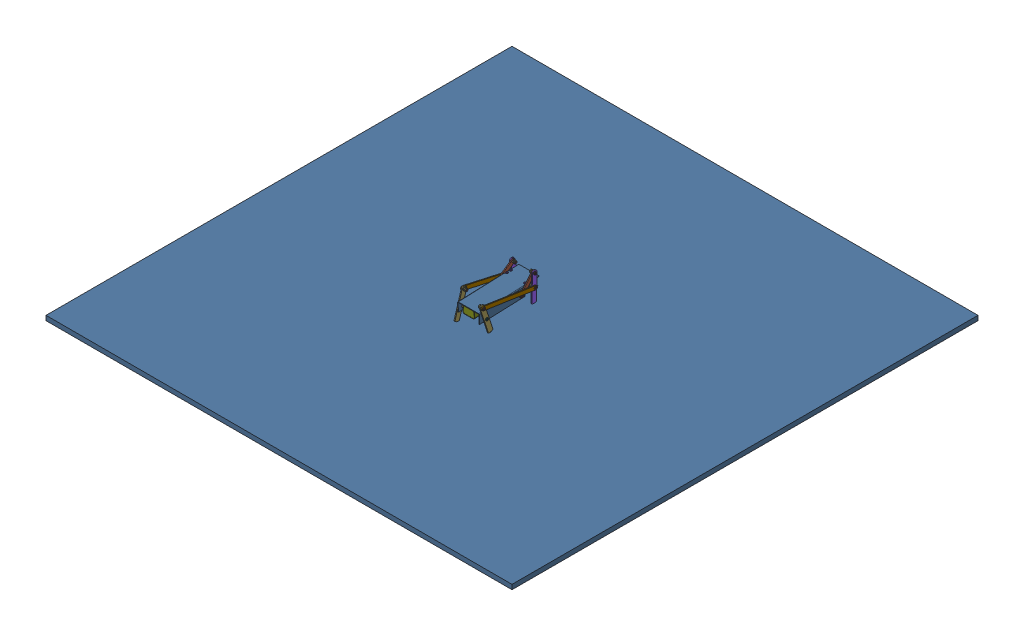
SolidWorks assembly Walking_Robot_(assembly), configuration Default. Lengths in mm.
Overall size (1000 78.05 1000).
80 component instances, 30 part files, 34 mates.
Components (placement in the parent):
- Walking_robot_(fixed_body)-1: Walking_robot_(fixed_body) [Default] at (18.9384 53.2482 -95.4555) x (0 -0.038992 0.99924) z (1 0 0) size (130 25.8 61.22)
  - ELENCO GEAR BOX 01-1: ELENCO GEAR BOX 01 [Default] at origin size (64.7 22.22 44.45)
  - ELENCO DC Motor 3V-1: ELENCO DC Motor 3V [Predeterminado] at (28.3843 11.811 0) x (0 0 1) z (-1 0 0) size (22.78 22.72 39.63)
    - ELENCO MOTOR HOUSING 01-1: ELENCO MOTOR HOUSING 01 [Predeterminado] at (0 0 24.0663) size (21.61 21.6 25.37)
    - ELENCO FRONT BUSHING-1: ELENCO FRONT BUSHING [Predeterminado] at (0 0 28.0103) x (0.939098 -0.34365 0) z (0 0 1) size (4.5 4.5 0.5)
    - ELENCO MOTOR BACK 01-1: ELENCO MOTOR BACK 01 [Predeterminado] at (0 0 4.731) x (-1 0 0) z (0 0 -1) size (21.23 21.59 3.58)
    - Terminal3V-1: Terminal3V [Predeterminado] at (0 -8.7 5.331) x (1 0 0) z (0 1 0) size (2.9 8 0.4)
    - Terminal3V-2: Terminal3V [Predeterminado] at (0 8.7 5.331) x (1 0 0) z (0 1 0) size (2.9 8 0.4)
    - ELENCO ARMATURE 01-1: ELENCO ARMATURE 01 [Predeterminado] at (0 0 36.9603) x (-0.892263 0.451515 0) z (0 0 1) size (17 16.86 36.46)
    - Enrolamento3V-1: Enrolamento3V [Predeterminado] at (2.0691 4.0889 14.4603) x (0.892263 -0.451515 0) z (0 0 1) size (7 3 16)
    - Enrolamento3V-2: Enrolamento3V [Predeterminado] at (-4.5756 -0.2525 14.4603) x (-0.055108 0.99848 0) z (0 0 1) size (7 3 16)
    - Enrolamento3V-3: Enrolamento3V [Predeterminado] at (2.5065 -3.8363 14.4603) x (-0.837155 -0.546965 0) z (0 0 1) size (7 3 16)
  - Walking_robot_(bolt_2_5x5)-1: Walking_robot_(bolt_2_5x5) [Default] at (-18.85 -1 19.55) x (0 -1 0) z (-0.551694 0 0.834047) size (6.57 4.4 4.4)
  - Walking_robot_(nut_2_5)-1: Walking_robot_(nut_2_5) [Default] at (-18.85 2.368 19.55) x (0.999996 0 -0.002907) z (0 -1 0) size (5.74 5.33 2.2)
  - Walking_robot_(bolt_2_5x5)-2: Walking_robot_(bolt_2_5x5) [Default] at (-18.85 -1 -19.55) x (0 -1 0) z (-0.551694 0 0.834047) size (6.57 4.4 4.4)
  - Walking_robot_(bolt_2_5x5)-3: Walking_robot_(bolt_2_5x5) [Default] at (-10.35 -1 19.55) x (0 -1 0) z (-0.551694 0 0.834047) size (6.57 4.4 4.4)
  - Walking_robot_(bolt_2_5x5)-4: Walking_robot_(bolt_2_5x5) [Default] at (-10.35 -1 -19.55) x (0 -1 0) z (-0.551694 0 0.834047) size (6.57 4.4 4.4)
  - Walking_robot_(nut_2_5)-2: Walking_robot_(nut_2_5) [Default] at (-18.85 2.368 -19.55) x (0.999996 0 -0.002907) z (0 -1 0) size (5.74 5.33 2.2)
  - Walking_robot_(nut_2_5)-3: Walking_robot_(nut_2_5) [Default] at (-10.35 2.368 19.55) x (0.999996 0 -0.002907) z (0 -1 0) size (5.74 5.33 2.2)
  - Walking_robot_(nut_2_5)-4: Walking_robot_(nut_2_5) [Default] at (-10.35 2.368 -19.55) x (0.999996 0 -0.002907) z (0 -1 0) size (5.74 5.33 2.2)
  - Walking_robot_(main_body)-1: Walking_robot_(main_body) [Default] at (42.9 -1 0) x (0 0 1) z (-1 0 0) size (46.5 20 130)
  - Walking_robot_(bolt_3x10)-1: Walking_robot_(bolt_3x10) [Default] at (3.9 11.5 -26.63) x (0 0 -1) z (1 0 0) size (11.98 5.4 5.4)
  - Walking_robot_(nut_3)-1: Walking_robot_(nut_3) [Default] at (3.9 11.5 -19.75) size (6.75 5.87 2.78)
  - Walking_robot_(bolt_3x10)-2: Walking_robot_(bolt_3x10) [Default] at (3.9 11.5 26.63) x (0 0 1) z (-0.923728 -0.383049 0) size (11.98 5.4 5.4)
  - Walking_robot_(nut_3)-7: Walking_robot_(nut_3) [Default] at (3.9 11.5 -22.25) size (6.75 5.87 2.78)
  - Walking_robot_(nut_3)-9: Walking_robot_(nut_3) [Default] at (3.9 11.5 19.75) size (6.75 5.87 2.78)
  - Walking_robot_(nut_3)-11: Walking_robot_(nut_3) [Default] at (3.9 11.5 17.25) size (6.75 5.87 2.78)
  - Walking_robot_(spacer1)-1: Walking_robot_(spacer1) [Default] at (3.9 11.5 23.25) size (6 6 1.38)
  - Walking_robot_(spacer1)-2: Walking_robot_(spacer1) [Default] at (3.9 11.5 -24.63) size (6 6 1.38)
  - Walking_robot_(spacer2)-1: Walking_robot_(spacer2) [Default] at (81.9 11.5 23.25) size (6 6 3.38)
  - Walking_robot_(spacer2)-2: Walking_robot_(spacer2) [Default] at (81.9 11.5 -26.63) size (6 6 3.38)
  - Walking_robot_(bolt_3x12)-2: Walking_robot_(bolt_3x12) [Default] at (81.9 11.5 28.634) x (0 0 1) z (-1 0 0) size (13.98 5.4 5.4)
  - Walking_robot_(bolt_3x12)-3: Walking_robot_(bolt_3x12) [Default] at (81.9 11.5 -28.634) x (0 0 -1) z (0.923728 0.383049 0) size (13.98 5.4 5.4)
  - Walking_robot_(nut_3)-8: Walking_robot_(nut_3) [Default] at (81.9 11.5 -22.25) size (6.75 5.87 2.78)
  - Walking_robot_(nut_3)-6: Walking_robot_(nut_3) [Default] at (81.9 11.5 -19.75) size (6.75 5.87 2.78)
  - Walking_robot_(nut_3)-12: Walking_robot_(nut_3) [Default] at (81.9 11.5 17.25) size (6.75 5.87 2.78)
  - Walking_robot_(nut_3)-10: Walking_robot_(nut_3) [Default] at (81.9 11.5 19.75) size (6.75 5.87 2.78)
  - PR2007 9 Volt Battery-1: PR2007 9 Volt Battery [Default] at (69.0962 8.1788 -0.6579) x (0 0 -1) z (0 1 0) size (25.25 47.81 16.41)
- ELENCO PINION  8T 01-1: ELENCO PINION  8T 01 [Default] at (18.9384 41.7805 -104.4855) x (0 -0.038992 0.99924) z (0.15938 0.986466 0.038494) size (4 4.57 4.57)
- Walking_robot_(assembled_first_axle)-1: Walking_robot_(assembled_first_axle) [Default] at (18.9384 31.4407 -126.8367) x (0 0.04551 -0.998964) z (1 0 0) size (20.72 20.72 40.75)
  - SHAFT 2 X 40-1: SHAFT 2 X 40 [Default] at (-15.216 11.557 0) x (-0.026375 -0.999652 0) z (0 0 1) size (2 2 40)
  - pCROWN GEAR 36T X 10T R01-1: pCROWN GEAR 36T X 10T R01 [Default] at (-15.216 11.557 -3.465) x (0 0 1) z (-0.986294 -0.164995 0) size (8.17 18 18)
  - ELENCO COLLAR 01-1: ELENCO COLLAR 01 [Default] at (-15.216 11.557 -15.875) x (0 0 -1) z (1 0 0) size (4.5 5 5)
  - ELENCO COLLAR 01-2: ELENCO COLLAR 01 [Default] at (-15.216 11.557 15.875) x (0 0 1) z (-0.923728 -0.383049 0) size (4.5 5 5)
- pCOMPOUND GEAR 40T X 10T GREEN R01-1: pCOMPOUND GEAR 40T X 10T GREEN R01 [Default] at (9.0224 42.2932 -111.1105) x (1 0 0) z (0 -0.686905 0.726747) size (6.08 20.96 20.96)
- Walking_robot_(assembled_second_axle)-1: Walking_robot_(assembled_second_axle) [Default] at (19.0544 21.5771 -145.3171) x (0 -0.376255 -0.926516) z (1 0 0) size (22.69 20.96 65.22)
  - SHAFT 3 X 52-1: SHAFT 3 X 52 [Default] at (-27.916 11.557 0) x (-0.087364 -0.996176 0) z (0 0 1) size (3 3 52)
  - ELENCO CRANK ARM 01-1: ELENCO CRANK ARM 01 [Default] at (-27.916 11.557 -23.446) x (0 0 -1) z (-0.996176 0.087364 0) size (10.76 6 14)
  - ELENCO CRANK ARM 01-2: ELENCO CRANK ARM 01 [Default] at (-27.916 11.557 23.2184) x (0 0 1) z (0.996176 -0.087364 0) size (10.76 6 14)
  - pCOMPOUND GEAR 40T X 10T GREEN R01a-1: pCOMPOUND GEAR 40T X 10T GREEN R01a [Default] at (-27.916 11.557 -12.742) x (0 0 -1) z (1 0 0) size (3.25 20.96 20.96)
  - Walking_robot_(nut_3)-1: Walking_robot_(nut_3) [Default] at (-35.8854 12.2559 20.7184) size (6.75 5.87 2.78)
  - Walking_robot_(nut_3)-2: Walking_robot_(nut_3) [Default] at (-19.9466 10.8581 -23.446) size (6.75 5.87 2.78)
  - Walking_robot_(bolt_3x10)-1: Walking_robot_(bolt_3x10) [Default] at (-35.8854 12.2559 30.5184) x (0 0 1) z (-1 0 0) size (11.98 5.4 5.4)
  - Walking_robot_(bolt_3x10)-2: Walking_robot_(bolt_3x10) [Default] at (-19.9466 10.8581 -30.746) x (0 0 -1) z (1 0 0) size (11.98 5.4 5.4)
- pCOMPOUND GEAR 40T X 10T RED R01-1: pCOMPOUND GEAR 40T X 10T RED R01 [Default] at (12.3884 42.7884 -123.8009) x (1 0 0) z (0 -0.583796 0.8119) size (6.08 20.96 20.96)
- Walking_robot_(legs)-1: Walking_robot_(legs) [Default] at (47.5729 47.9338 -116.7279) x (0 0.03187 0.999492) z (-1 0 0) size (10 60.41 2)
- Walking_robot_(legs)-2: Walking_robot_(legs) [Default] at (-7.6916 40.601 -130.5719) x (0 -0.233207 0.972427) z (-1 0 0) size (10 60.41 2)
- Walking_robot_(legs_lever1)-1: Walking_robot_(legs_lever1) [Default] at (-11.6916 60.0865 -36.7219) x (0 -0.976163 0.217038) z (1 0 0) size (8 120 2)
- Walking_robot_(legs_lever1)-2: Walking_robot_(legs_lever1) [Default] at (47.5729 60.9356 -21.2758) x (0 -0.988645 0.15027) z (1 0 0) size (8 120 2)
- Walking_robot_(floor)-1: Walking_robot_(floor) [Default] at (39.0613 0 -76.9839) x (1 0 0) z (0 1 0) size (1000 1000 10)
- Walking_robot_(assembled_legs_lever2)-1: Walking_robot_(assembled_legs_lever2) [Default] at (28.0217 115.6355 -43.4429) x (0 0.821287 0.570516) z (-1 0 0) size (8 48 11.98)
  - Walking_robot_(legs_lever2)-1: Walking_robot_(legs_lever2) [Default] at (-88.5069 13.1493 33.7132) size (8 48 2)
  - Walking_robot_(bolt_3x10)-1: Walking_robot_(bolt_3x10) [Default] at (-88.5069 37.6493 37.7132) x (0 0 1) z (-1 0 0) size (11.98 5.4 5.4)
  - Walking_robot_(nut_3)-1: Walking_robot_(nut_3) [Default] at (-88.5069 37.6493 31.2132) size (6.75 5.87 2.78)
  - Walking_robot_(nut_3)-2: Walking_robot_(nut_3) [Default] at (-88.5069 37.6493 28.7132) size (6.75 5.87 2.78)
- Walking_robot_(assembled_legs_lever2)-2: Walking_robot_(assembled_legs_lever2) [Default] at (9.8596 -13.0114 -161.6923) x (0 -0.637546 -0.770412) z (1 0 0) size (8 48 11.98)
  - Walking_robot_(legs_lever2)-1: Walking_robot_(legs_lever2) [Default] at (-88.5069 13.1493 33.7132) size (8 48 2)
  - Walking_robot_(bolt_3x10)-1: Walking_robot_(bolt_3x10) [Default] at (-88.5069 37.6493 37.7132) x (0 0 1) z (-1 0 0) size (11.98 5.4 5.4)
  - Walking_robot_(nut_3)-1: Walking_robot_(nut_3) [Default] at (-88.5069 37.6493 31.2132) size (6.75 5.87 2.78)
  - Walking_robot_(nut_3)-2: Walking_robot_(nut_3) [Default] at (-88.5069 37.6493 28.7132) size (6.75 5.87 2.78)
- Walking_robot_(assembled_front_legs)-1: Walking_robot_(assembled_front_legs) [Default] at (11.8596 55.1181 -101.788) x (0 0.31209 -0.950053) z (1 0 0) size (10 60.4 11.98)
  - Walking_robot_(bolt_3x10)-1: Walking_robot_(bolt_3x10) [Default] at (-88.5069 37.6493 37.7132) x (0 0 1) z (-1 0 0) size (11.98 5.4 5.4)
  - Walking_robot_(nut_3)-1: Walking_robot_(nut_3) [Default] at (-88.5069 37.6493 31.2132) size (6.75 5.87 2.78)
  - Walking_robot_(nut_3)-2: Walking_robot_(nut_3) [Default] at (-88.5069 37.6493 28.7132) size (6.75 5.87 2.78)
  - analysisWalking_robot_(legs)-1: analysisWalking_robot_(legs) [Default] at (-88.5069 13.1493 33.7132) size (10 60.4 2)
- Walking_robot_(assembled_front_legs)-2: Walking_robot_(assembled_front_legs) [Default] at (26.0217 53.0296 74.0242) x (0 0.289433 0.957198) z (-1 0 0) size (10 60.4 11.98)
  - Walking_robot_(bolt_3x10)-1: Walking_robot_(bolt_3x10) [Default] at (-88.5069 37.6493 37.7132) x (0 0 1) z (-1 0 0) size (11.98 5.4 5.4)
  - Walking_robot_(nut_3)-1: Walking_robot_(nut_3) [Default] at (-88.5069 37.6493 31.2132) size (6.75 5.87 2.78)
  - Walking_robot_(nut_3)-2: Walking_robot_(nut_3) [Default] at (-88.5069 37.6493 28.7132) size (6.75 5.87 2.78)
  - analysisWalking_robot_(legs)-1: analysisWalking_robot_(legs) [Default] at (-88.5069 13.1493 33.7132) size (10 60.4 2)
Mates (geometry in assembly coordinates):
- Concentric1: concentric: cylinder of Walking_robot_(fixed_body)-1/ELENCO DC Motor 3V-1/ELENCO ARMATURE 01-1 through (18.9384 40.3589 -68.0532) axis (0 0.038992 -0.99924) radius 1; cylinder of ELENCO PINION  8T 01-1 through (18.9384 41.6246 -100.4885) axis (0 0.038992 -0.99924) radius 0.9779
- Coincident1: coincident: plane of Walking_robot_(fixed_body)-1/ELENCO DC Motor 3V-1/ELENCO ARMATURE 01-1 through (18.9384 41.7805 -104.4855) normal (0 0.038992 -0.99924); plane of ELENCO PINION  8T 01-1 through (18.9384 41.7805 -104.4855) normal (0 0.038992 -0.99924)
- Coincident2: coincident: plane of Walking_robot_(fixed_body)-1/ELENCO GEAR BOX 01-1 through (3.0634 56.5111 -95.3281) normal (-1 0 0); plane of Walking_robot_(assembled_first_axle)-1/ELENCO COLLAR 01-1 through (3.0634 42.2932 -111.1105) normal (1 0 0)
- Concentric2: concentric: cylinder of Walking_robot_(fixed_body)-1/ELENCO GEAR BOX 01-1 through (-3.2866 42.2932 -111.1105) axis (1 0 0) radius 1; cylinder of Walking_robot_(assembled_first_axle)-1/SHAFT 2 X 40-1 through (38.9384 42.2932 -111.1105) axis (-1 0 0) radius 1
- GearMate1: gear = 36 : 8 mm: circle of ELENCO PINION  8T 01-1; circle of Walking_robot_(assembled_first_axle)-1/pCROWN GEAR 36T X 10T R01-1
- Concentric4: concentric: cylinder of Walking_robot_(assembled_first_axle)-1/SHAFT 2 X 40-1 through (38.9384 42.2932 -111.1105) axis (-1 0 0) radius 1; cylinder of pCOMPOUND GEAR 40T X 10T GREEN R01-1 through (58.3975 42.2932 -111.1105) axis (-1 0 0) radius 1
- Coincident3: coincident: plane of Walking_robot_(fixed_body)-1/ELENCO GEAR BOX 01-1 through (3.5714 56.5111 -95.3281) normal (1 0 0); plane of pCOMPOUND GEAR 40T X 10T GREEN R01-1 through (3.5714 42.2932 -111.1105) normal (-1 0 0)
- Coincident4: coincident: plane of Walking_robot_(fixed_body)-1/ELENCO GEAR BOX 01-1 through (3.0634 56.5111 -95.3281) normal (-1 0 0); plane of Walking_robot_(assembled_second_axle)-1/ELENCO CRANK ARM 01-1 through (3.0634 42.7884 -123.8009) normal (1 0 0)
- Concentric5: concentric: cylinder of Walking_robot_(fixed_body)-1/ELENCO GEAR BOX 01-1 through (-3.2866 42.7884 -123.8009) axis (1 0 0) radius 1.5; cylinder of Walking_robot_(assembled_second_axle)-1/SHAFT 3 X 52-1 through (45.0544 42.7884 -123.8009) axis (-1 0 0) radius 1.5
- Concentric6: concentric: cylinder of Walking_robot_(assembled_second_axle)-1/SHAFT 3 X 52-1 through (45.0544 42.7884 -123.8009) axis (-1 0 0) radius 1.5; cylinder of pCOMPOUND GEAR 40T X 10T RED R01-1 through (6.9374 42.7884 -123.8009) axis (1 0 0) radius 1.5
- Coincident5: coincident: plane of Walking_robot_(assembled_second_axle)-1/pCOMPOUND GEAR 40T X 10T GREEN R01a-1 through (6.9374 42.7884 -123.8009) normal (1 0 0); plane of pCOMPOUND GEAR 40T X 10T RED R01-1 through (6.9374 42.7884 -123.8009) normal (-1 0 0)
- GearMate2: gear = 40 : 10 mm: circle of Walking_robot_(assembled_first_axle)-1/pCROWN GEAR 36T X 10T R01-1; circle of pCOMPOUND GEAR 40T X 10T RED R01-1
- GearMate3: gear = 40 : 10 mm: circle of pCOMPOUND GEAR 40T X 10T RED R01-1; circle of pCOMPOUND GEAR 40T X 10T GREEN R01-1
- GearMate4: gear = 40 : 10 mm: circle of pCOMPOUND GEAR 40T X 10T GREEN R01-1; circle of Walking_robot_(assembled_second_axle)-1/pCOMPOUND GEAR 40T X 10T GREEN R01a-1
- Coincident7: coincident: circle of Walking_robot_(assembled_second_axle)-1/ELENCO CRANK ARM 01-1; circle of Walking_robot_(legs)-2
- Coincident12: coincident: circle of Walking_robot_(assembled_second_axle)-1/ELENCO CRANK ARM 01-2; circle of Walking_robot_(legs)-1
- Concentric15: concentric: cylinder of Walking_robot_(legs)-2 through (-9.6916 39.1423 -130.9217) axis (1 0 0) radius 1.5; cylinder of Walking_robot_(legs_lever1)-1 through (-9.6916 39.1423 -130.9217) axis (-1 0 0) radius 1.5
- Coincident18: coincident: plane of Walking_robot_(legs)-2 through (-9.6916 19.8252 -135.5543) normal (-1 0 0); plane of Walking_robot_(legs_lever1)-1 through (-9.6916 63.4506 -21.5914) normal (1 0 0)
- Coincident19: coincident: plane of Walking_robot_(legs)-1 through (47.5729 26.5798 -116.047) normal (1 0 0); plane of Walking_robot_(legs_lever1)-2 through (47.5729 63.2648 -5.9518) normal (-1 0 0)
- Concentric17: concentric: cylinder of Walking_robot_(legs)-1 through (45.5729 46.4345 -116.6801) axis (1 0 0) radius 1.5; cylinder of Walking_robot_(legs_lever1)-2 through (49.5729 46.4345 -116.6801) axis (-1 0 0) radius 1.5
- Coincident20: coincident: plane of Walking_robot_(floor)-1 through (39.0613 0 -76.9839) normal (0 -1 0); plane of assembly through (0 0 0) normal (0 1 0)
- Coincident22: coincident: plane of Walking_robot_(legs)-2 through (-7.6916 19.8252 -135.5543) normal (1 0 0); plane of Walking_robot_(assembled_legs_lever2)-1/Walking_robot_(legs_lever2)-1 through (-7.6916 41.6048 -92.0068) normal (-1 0 0)
- Concentric19: concentric: cylinder of Walking_robot_(legs)-2 through (-9.6916 64.4255 -124.8583) axis (1 0 0) radius 1.5; cylinder of Walking_robot_(assembled_legs_lever2)-1/Walking_robot_(bolt_3x10)-1 through (0.3084 64.4255 -124.8583) axis (-1 0 0) radius 1.5
- Concentric20: concentric: cylinder of Walking_robot_(fixed_body)-1/Walking_robot_(bolt_3x10)-1 through (2.3084 41.6048 -92.0068) axis (-1 0 0) radius 1.5; cylinder of Walking_robot_(assembled_legs_lever2)-1/Walking_robot_(legs_lever2)-1 through (-7.6916 41.6048 -92.0068) axis (1 0 0) radius 1.5
- Concentric21: concentric: cylinder of Walking_robot_(fixed_body)-1/Walking_robot_(bolt_3x10)-2 through (35.5684 41.6048 -92.0068) axis (1 0 0) radius 1.5; cylinder of Walking_robot_(assembled_legs_lever2)-2/Walking_robot_(legs_lever2)-1 through (45.5729 41.6048 -92.0068) axis (-1 0 0) radius 1.5
- Coincident23: coincident: plane of Walking_robot_(legs)-1 through (45.5729 26.5798 -116.047) normal (-1 0 0); plane of Walking_robot_(assembled_legs_lever2)-2/Walking_robot_(legs_lever2)-1 through (45.5729 41.6048 -92.0068) normal (1 0 0)
- Concentric22: concentric: cylinder of Walking_robot_(legs)-1 through (45.5729 72.4213 -117.5087) axis (1 0 0) radius 1.5; cylinder of Walking_robot_(assembled_legs_lever2)-2/Walking_robot_(bolt_3x10)-1 through (37.5729 72.4213 -117.5087) axis (1 0 0) radius 1.5
- Concentric23: concentric: cylinder of Walking_robot_(fixed_body)-1/Walking_robot_(bolt_3x12)-3 through (2.3044 38.5635 -14.0662) axis (-1 0 0) radius 1.5; cylinder of Walking_robot_(assembled_front_legs)-2/analysisWalking_robot_(legs)-1 through (-9.6916 38.5635 -14.0662) axis (1 0 0) radius 1.5
- Coincident24: coincident: plane of Walking_robot_(legs)-2 through (-9.6916 19.8252 -135.5543) normal (-1 0 0); plane of Walking_robot_(assembled_front_legs)-2/analysisWalking_robot_(legs)-1 through (-9.6916 19.5489 -8.3166) normal (-1 0 0)
- Concentric24: concentric: cylinder of Walking_robot_(legs_lever1)-1 through (-9.6916 63.4506 -21.5914) axis (-1 0 0) radius 1.5; cylinder of Walking_robot_(assembled_front_legs)-2/Walking_robot_(bolt_3x10)-1 through (-1.6916 63.4506 -21.5914) axis (-1 0 0) radius 1.5
- Concentric25: concentric: cylinder of Walking_robot_(fixed_body)-1/Walking_robot_(bolt_3x12)-2 through (35.5724 38.5635 -14.0662) axis (1 0 0) radius 1.5; cylinder of Walking_robot_(assembled_front_legs)-1/analysisWalking_robot_(legs)-1 through (47.5729 38.5635 -14.0662) axis (-1 0 0) radius 1.5
- Coincident25: coincident: plane of Walking_robot_(legs)-1 through (47.5729 26.5798 -116.047) normal (1 0 0); plane of Walking_robot_(assembled_front_legs)-1/analysisWalking_robot_(legs)-1 through (47.5729 19.6908 -20.2658) normal (1 0 0)
- Concentric26: concentric: cylinder of Walking_robot_(legs_lever1)-2 through (49.5729 63.2648 -5.9518) axis (-1 0 0) radius 1.5; cylinder of Walking_robot_(assembled_front_legs)-1/Walking_robot_(bolt_3x10)-1 through (39.5729 63.2648 -5.9518) axis (1 0 0) radius 1.5
- Tangent1: tangent anti-aligned: plane of Walking_robot_(floor)-1 through (39.0613 10 -76.9839) normal (0 1 0); cylinder of Walking_robot_(assembled_front_legs)-2/analysisWalking_robot_(legs)-1 through (-9.6916 19.5489 -8.3166) axis (1 0 0) radius 9.5489
